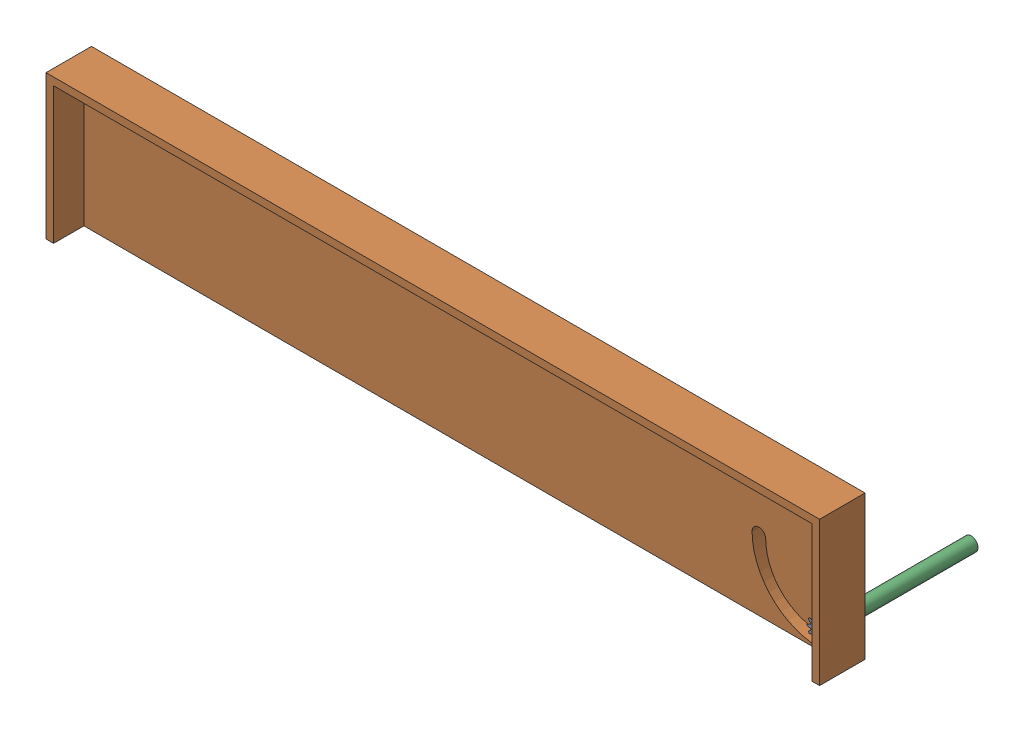
SolidWorks assembly Testing Gear, configuration Default. Lengths in mm.
Overall size (510 95.05 120).
3 component instances, 3 part files, 4 mates.
Components (placement in the parent):
- Gear-1: Gear [Default] at (-18.2164 -39.4262 46.3642) x (0.871607 -0.490205 0) z (0 0 1) size (16.23 16.23 10)
- Cover-1: Cover [Default] at (-508.1712 44.5738 51.3642) size (510 95 30)
- Shaft-1: Shaft [Default] at (-18.2164 -39.4262 -48.6358) x (0.99894 -0.046034 0) z (0 0 1) size (9 9 100)
Mates (geometry in assembly coordinates):
- PathMate2: path: circle of assembly; point of Gear-1; circle of Cover-1
- Coincident1: coincident aligned: plane of Gear-1 through (-18.2164 -39.4262 51.3642) normal (0 0 1); plane of Cover-1 through (-508.1712 44.5738 51.3642) normal (0 0 1)
- Concentric1: concentric aligned: cylinder of Gear-1 through (-18.2164 -39.4262 51.3642) axis (0 0 -1) radius 4.5; cylinder of Shaft-1 through (-18.2164 -39.4262 51.3642) axis (0 0 -1) radius 4.5
- Coincident2: coincident aligned: plane of Cover-1 through (-508.1712 44.5738 51.3642) normal (0 0 1); plane of Shaft-1 through (-18.2164 -39.4262 51.3642) normal (0 0 1)
